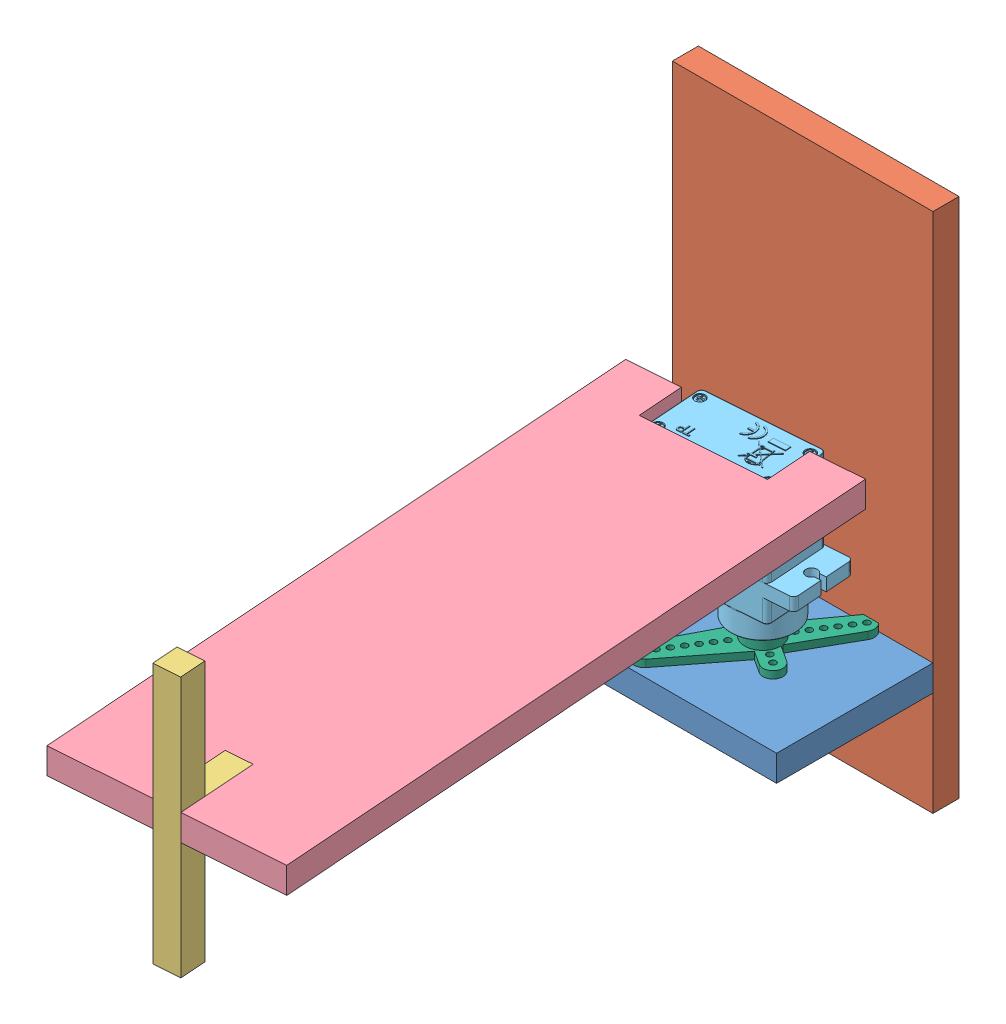
SolidWorks assembly Assem3, configuration Default. Lengths in mm.
Overall size (55.09 100 137.16).
8 component instances, 6 part files, 4 mates.
Components (placement in the parent):
- Assem1-1: Assem1 [Default] at (21.7734 -1.9754 34.6243) size (50 100 35)
  - sideServoHolder-1: sideServoHolder [Default] at (28.795 22.9449 66.6654) size (50 5 35)
  - solarSupport-1: solarSupport [Default] at (-21.205 102.9449 36.6654) x (0 0 -1) z (0 -1 0) size (5 50 100)
- Assem2-1: Assem2 [Default] at (52.8078 97.7065 216.5566) x (-0.997394 0 0.072151) z (0 -1 0) size (43 123.53 54.15)
  - base-1: base [Default] at (14.9891 15.9578 15.7892) size (5 15 50)
  - stand-1: stand [Default] at (38.9891 15.9578 38.2892) x (0 0 1) z (-1 0 0) size (5 120 43)
  - SG90 - Micro Servo 9g - Tower Pro.1-1: SG90 - Micro Servo 9g - Tower Pro.1 [Peça] at (17.2391 133.2838 50.637) x (1 0 0) z (0 -1 0) size (32.1 29.95 12.4)
- arm-1: arm [Peça] at (31.1337 25.9695 84.4924) x (-0.539992 0 0.84167) z (0.84167 0 0.539992) size (34.5 3.8 16.7)
Mates (geometry in assembly coordinates):
- Coincident1: coincident: plane of assembly; plane of assembly; plane of Assem2-1/SG90 - Micro Servo 9g - Tower Pro.1-1 through (31.1337 27.7695 84.4924) normal (0 -1 0); plane of arm-1 through (31.1337 27.7695 84.4924) normal (0 1 0)
- Concentric1: concentric: cylinder of assembly; cylinder of assembly; cylinder of Assem2-1/SG90 - Micro Servo 9g - Tower Pro.1-1 through (31.1337 27.7695 84.4924) axis (0 -1 0) radius 0.8; cylinder of arm-1 through (31.1337 25.9695 84.4924) axis (0 -1 0) radius 1.05
- Coincident5: coincident: plane of assembly; plane of assembly; plane of Assem1-1/sideServoHolder-1 through (50.5684 25.9695 101.2897) normal (0 1 0); plane of arm-1 through (31.1337 25.9695 84.4924) normal (0 -1 0)
- Coincident6: coincident: plane of assembly; plane of assembly; plane of Assem1-1/sideServoHolder-1 through (50.5684 25.9695 101.2897) normal (0 1 0); plane of arm-1 through (31.1337 25.9695 84.4924) normal (0 -1 0)
